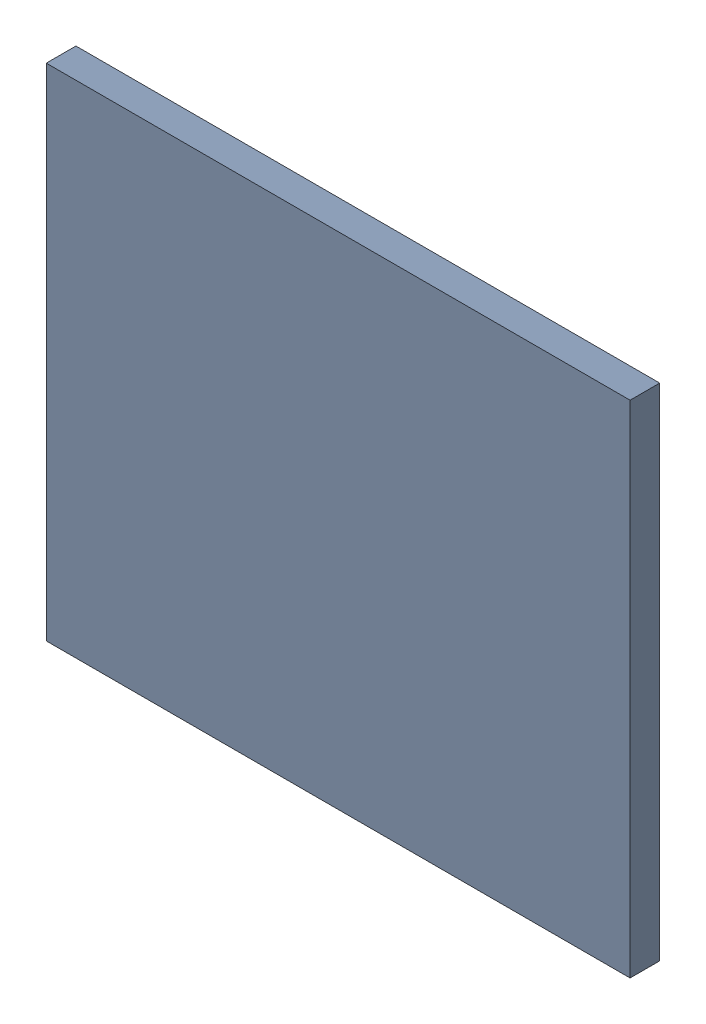
SolidWorks assembly Pad R2-2(29.95mm,40mm) on Top Layer, configuration Predeterminado. Lengths in mm.
Overall size (0.7 0.6 0.04).
2 component instances, 1 part files, 0 mates.
Components (placement in the parent):
- Pad R2-2(29.95mm,40mm) on Top Layer-1-1: Pad R2-2(29.95mm,40mm) on Top Layer-1 [Predeterminado] at (-68.317 -44.187 -0.0457) size (0.7 0.6 0.04)
  - Pad R2-2(29.95mm,40mm) on Top Layer-Part-1-1: Pad R2-2(29.95mm,40mm) on Top Layer-Part-1 [Predeterminado] at origin size (0.7 0.6 0.04)
